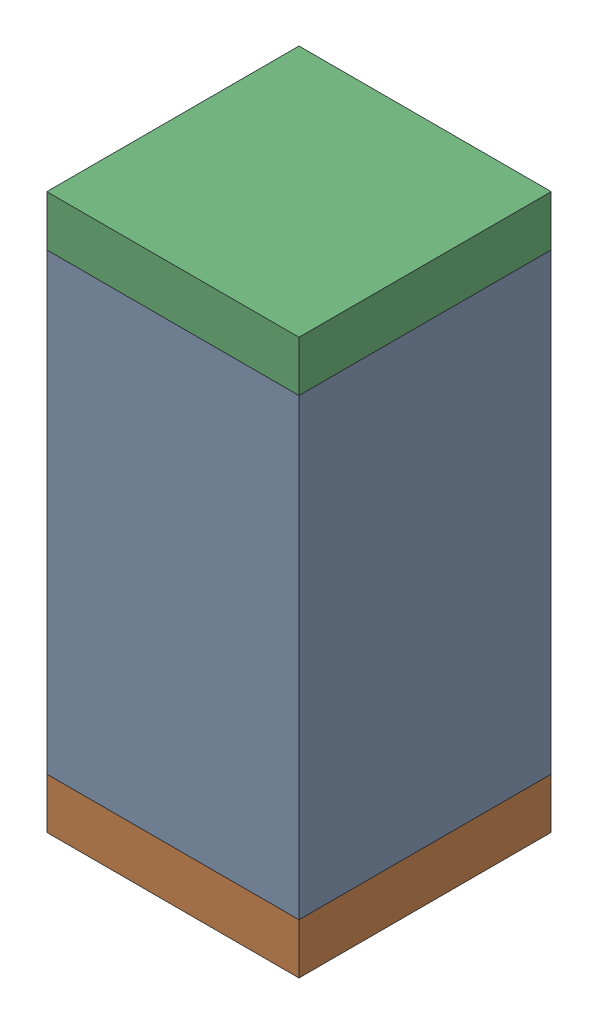
SolidWorks assembly C33, configuration Default. Lengths in mm.
Overall size (0.5 1.1 0.5).
6 component instances, 2 part files, 0 mates.
Components (placement in the parent):
- 791586336-1: 791586336 [Default] at (113.05 29.2 0) size (0.5 0.9 0.5)
  - Extruded_8-1: Extruded_8 [Default] at origin size (0.5 0.9 0.5)
- 810157360-1: 810157360 [Default] at (113.05 28.7 0) size (0.5 0.1 0.5)
  - Extruded_9-1: Extruded_9 [Default] at origin size (0.5 0.1 0.5)
- 810157360-2: 810157360 [Default] at (113.05 29.7 0) size (0.5 0.1 0.5)
  - Extruded_9-1: Extruded_9 [Default] at origin size (0.5 0.1 0.5)
